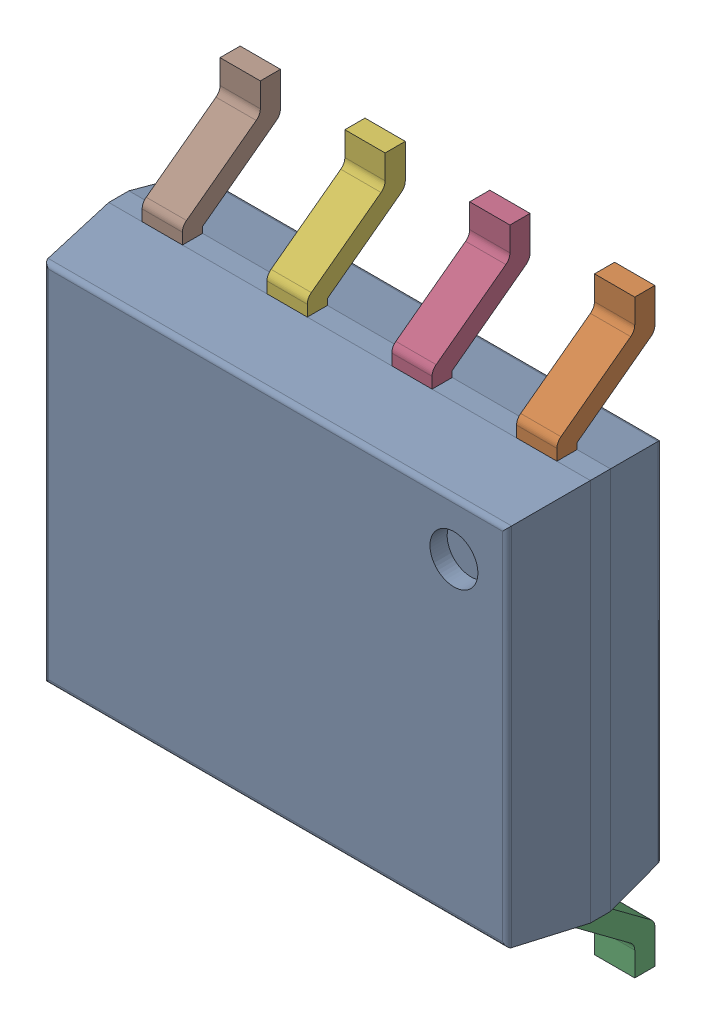
SolidWorks assembly IC7_1.step, configuration Default. Lengths in mm.
Overall size (4.9 6 1.75).
3 component instances, 2 part files, 0 mates.
Components (placement in the parent):
- 6348793408_1.step-11: 6348793408_1.step [Default] at (432.06 250.881 0) x (0 -1 0) z (0 0 1) size (6 4.9 1.75)
  - Body-1216_1.step-21: Body-1216_1.step [Default] at origin size (3.9 4.9 1.57)
  - PinsArrayLR-1217_1.step-21: PinsArrayLR-1217_1.step [Default] at origin size (6 4.22 1)
